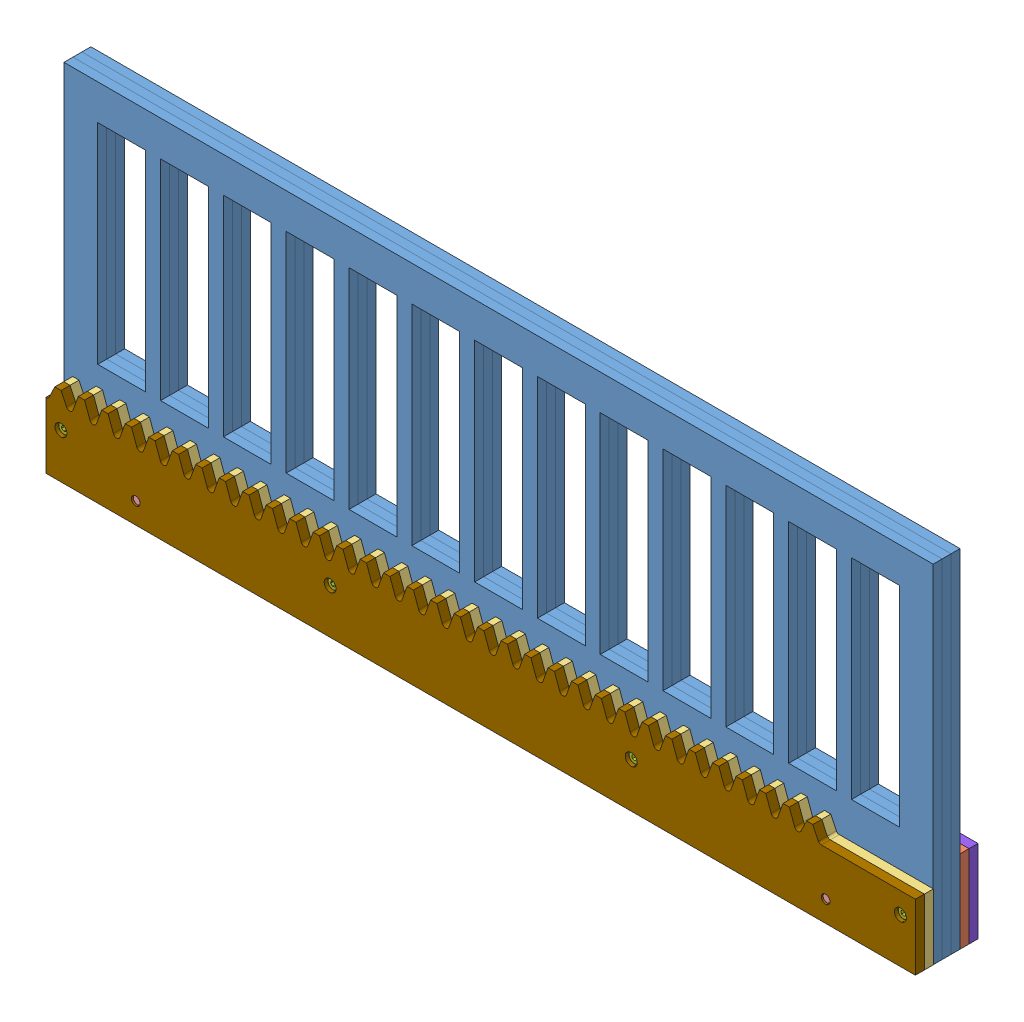
SolidWorks assembly grille-complet, configuration Défaut. Lengths in mm.
Overall size (290.66 121.96 23).
19 component instances, 9 part files, 44 mates.
Components (placement in the parent):
- grille-1: grille [Défaut] at (-123.12 -59.7841 0) size (290.6 116 3)
- grille-bas-1-1: grille-bas-1 [Défaut] at (-123.1215 -59.7841 -3) size (290.6 27.62 3)
- grille-cremaillere-1-1: grille-cremaillere-1 [Défaut] at (151.8274 -59.7841 12) x (-1 0 0) z (0 0 -1) size (290.66 27.62 3)
- grille-axe-d3x20-1: grille-axe-d3x20 [Défaut] at (-97.0485 -52.7841 -5.5) x (0.990021 0.140917 0) z (0.140917 -0.990021 0) size (3 20 3)
- grille-poulie-d20-1: grille-poulie-d20 [Défaut] at (-97.0485 -52.7841 3.2376) x (0.249924 -0.968265 0) z (-0.968265 -0.249924 0) size (20.21 12 20.21)
- grille-poulie-d20-2: grille-poulie-d20 [Défaut] at (133.5488 -52.7841 3.6069) x (0.939295 0.34311 0) z (0.34311 -0.939295 0) size (20.21 12 20.21)
- grille-axe-d3x20-2: grille-axe-d3x20 [Défaut] at (133.5488 -52.7841 -5.5) x (0.725366 0.688363 0) z (0.688363 -0.725366 0) size (3 20 3)
- ecrou-h-1: ecrou-h [6007 HU M2] at (-122.0485 -44.7841 -3) x (1 0 0) z (0 -1 0) size (4 1.6 4.62)
- vis-chc-1: vis-chc [Vis CHC M2x20] at (-122.0485 -44.7841 12) x (-0.903483 -0.428623 0) z (-0.428623 0.903483 0) size (3.8 22 3.8)
- vis-chc-2: vis-chc [Vis CHC M2x20] at (-32.0485 -44.7841 12) x (0.724363 -0.689419 0) z (-0.689419 -0.724363 0) size (3.8 22 3.8)
- vis-chc-3: vis-chc [Vis CHC M2x20] at (68.6083 -44.7841 12) x (0.282213 -0.959352 0) z (-0.959352 -0.282213 0) size (3.8 22 3.8)
- vis-chc-4: vis-chc [Vis CHC M2x20] at (158.6083 -44.7841 12) x (-0.282213 0.959352 0) z (0.959352 0.282213 0) size (3.8 22 3.8)
- grille-2: grille [Défaut] at (-123.12 -59.7841 3) size (290.6 116 3)
- grille-3: grille [Défaut] at (-123.12 -59.7841 6) size (290.6 116 3)
- grille-bas-2-1: grille-bas-2 [Défaut] at (-123.1215 -59.7841 -6) size (290.6 27.62 3)
- grille-cremaillere-2-1: grille-cremaillere-2 [Défaut] at (151.8274 -59.7841 15) x (-1 0 0) z (0 0 -1) size (290.66 27.62 3)
- ecrou-h-2: ecrou-h [6007 HU M2] at (-32.0485 -44.7841 -3) x (1 0 0) z (0 -1 0) size (4 1.6 4.62)
- ecrou-h-3: ecrou-h [6007 HU M2] at (68.6083 -44.7841 -3) x (1 0 0) z (0 -1 0) size (4 1.6 4.62)
- ecrou-h-4: ecrou-h [6007 HU M2] at (158.6083 -44.7841 -3) x (1 0 0) z (0 -1 0) size (4 1.6 4.62)
Mates (geometry in assembly coordinates):
- Coïncidente7: coincident anti-aligned: line of grille-axe-d3x20-1 through (-97.0485 -52.7841 14.3) axis (0 0 -1); line of grille-poulie-d20-1 through (-97.0485 -52.7841 3.2376) axis (0 0 1)
- Coïncidente12: coincident anti-aligned: line of Poulie D20-2 through (133.5488 -52.7841 3.6069) axis (0 0 1); line of grille-axe-d3x20-2 through (133.5488 -52.7841 14.3) axis (0 0 -1)
- Coïncidente22: coincident anti-aligned: plane of grille-1 through (-107.05 -50.784 3) normal (0 0 1); plane of grille-2 through (-107.05 -50.784 3) normal (0 0 -1)
- Coïncidente23: coincident aligned: plane of grille-1 through (-127.0485 56.2159 3) normal (0 1 0); plane of grille-2 through (-127.0485 56.2159 6) normal (0 1 0)
- Coïncidente24: coincident: line of grille-1 through (116 163.5503 -59.7841) axis (0 0 1); plane of grille-2 through (163.5503 56.2159 6) normal (1 0 0)
- Coïncidente26: coincident anti-aligned: plane of grille-2 through (-107.05 -50.784 6) normal (0 0 1); plane of grille-3 through (-107.05 -50.784 6) normal (0 0 -1)
- Coïncidente27: coincident aligned: plane of grille-2 through (-127.0485 56.2159 6) normal (0 1 0); plane of grille-3 through (-127.0485 56.2159 9) normal (0 1 0)
- Coïncidente28: coincident aligned: plane of grille-2 through (163.5503 56.2159 6) normal (1 0 0); plane of grille-3 through (163.5503 56.2159 9) normal (1 0 0)
- Coïncidente29: coincident aligned: plane of grille-1 through (-127.0485 56.2159 3) normal (-1 0 0); plane of grille-bas-1-1 through (-127.0485 -32.1591 0) normal (-1 0 0)
- Coïncidente30: coincident anti-aligned: plane of grille-1 through (-107.05 -50.784 0) normal (0 0 -1); plane of grille-bas-1-1 through (-127.0485 -59.7841 0) normal (0 0 1)
- Coïncidente32: coincident anti-aligned: plane of grille-cremaillere-1-1 through (124.3384 -36.6044 9) normal (0 0 -1); plane of grille-3 through (-107.05 -50.784 9) normal (0 0 1)
- Coïncidente33: coincident aligned: plane of grille-cremaillere-1-1 through (-127.0485 -37.7826 9) normal (-1 0 0); plane of grille-3 through (-127.0485 56.2159 9) normal (-1 0 0)
- Coïncidente35: coincident aligned: plane of grille-cremaillere-1-1 through (-127.0485 -59.7841 9) normal (0 -1 0); plane of grille-3 through (163.5503 -59.7841 9) normal (0 -1 0)
- Coïncidente36: coincident aligned: plane of grille-bas-1-1 through (-127.0485 -59.7841 0) normal (0 -1 0); plane of grille-cremaillere-1-1 through (-127.0485 -59.7841 9) normal (0 -1 0)
- Coïncidente37: coincident aligned: plane of grille-bas-1-1 through (-127.0485 -32.1591 0) normal (-1 0 0); plane of grille-bas-2-1 through (-127.0485 -32.1591 -3) normal (-1 0 0)
- Coïncidente38: coincident anti-aligned: plane of grille-bas-1-1 through (-127.0485 -59.7841 -3) normal (0 0 -1); plane of grille-bas-2-1 through (-127.0485 -59.7841 -3) normal (0 0 1)
- Coïncidente39: coincident aligned: plane of grille-bas-1-1 through (-127.0485 -32.1591 0) normal (0 1 0); plane of grille-bas-2-1 through (-127.0485 -32.1591 -3) normal (0 1 0)
- Coïncidente40: coincident aligned: plane of grille-cremaillere-1-1 through (163.6083 -37.7841 9) normal (1 0 0); plane of grille-cremaillere-2-1 through (163.6083 -37.7841 12) normal (1 0 0)
- Coïncidente41: coincident aligned: plane of grille-cremaillere-1-1 through (-127.0485 -59.7841 9) normal (0 -1 0); plane of grille-cremaillere-2-1 through (-127.0485 -59.7841 12) normal (0 -1 0)
- Coïncidente42: coincident anti-aligned: plane of grille-cremaillere-1-1 through (124.3384 -36.6044 12) normal (0 0 1); plane of grille-cremaillere-2-1 through (124.3384 -36.6044 12) normal (0 0 -1)
- Coaxiale2: concentric anti-aligned: cylinder of grille-axe-d3x20-2 through (133.5488 -52.7841 14.5) axis (0 0 -1) radius 1.5; cylinder of grille-bas-2-1 through (133.5488 -52.7841 -6) axis (0 0 1) radius 1.45
- Distance1: distance = 0.5 mm aligned: plane of grille-axe-d3x20-2 through (133.5488 -52.7841 -5.5) normal (0 0 -1); plane of grille-bas-2-1 through (-127.0485 -59.7841 -6) normal (0 0 -1)
- Coaxiale3: concentric aligned: cylinder of grille-axe-d3x20-1 through (-97.0485 -52.7841 14.5) axis (0 0 -1) radius 1.5; cylinder of grille-cremaillere-2-1 through (-97.0485 -52.7841 15) axis (0 0 -1) radius 1.45
- Distance2: distance = 0.5 mm aligned: plane of grille-axe-d3x20-1 through (-97.0485 -52.7841 -5.5) normal (0 0 -1); plane of grille-bas-2-1 through (-127.0485 -59.7841 -6) normal (0 0 -1)
- Coaxiale4: concentric aligned: cylinder of grille-cremaillere-2-1 through (-122.0485 -44.7841 12) axis (0 0 1) radius 2; cylinder of vis-chc-1 through (-122.0485 -44.7841 -8) axis (0 0 1) radius 1
- Coïncidente45: coincident anti-aligned: plane of grille-cremaillere-1-1 through (124.3384 -36.6044 12) normal (0 0 1); plane of vis-chc-1 through (-122.0485 -44.7841 12) normal (0 0 -1)
- Coaxiale7: concentric aligned: cylinder of grille-cremaillere-1-1 through (-32.0485 -44.7841 9) axis (0 0 1) radius 1; cylinder of vis-chc-2 through (-32.0485 -44.7841 -8) axis (0 0 1) radius 1
- Coaxiale8: concentric aligned: cylinder of grille-cremaillere-1-1 through (68.6083 -44.7841 9) axis (0 0 1) radius 1; cylinder of vis-chc-3 through (68.6083 -44.7841 -8) axis (0 0 1) radius 1
- Coaxiale9: concentric aligned: cylinder of grille-cremaillere-1-1 through (158.6083 -44.7841 9) axis (0 0 1) radius 1; cylinder of vis-chc-4 through (158.6083 -44.7841 -8) axis (0 0 1) radius 1
- Coïncidente46: coincident anti-aligned: plane of grille-cremaillere-1-1 through (124.3384 -36.6044 12) normal (0 0 1); plane of vis-chc-2 through (-32.0485 -44.7841 12) normal (0 0 -1)
- Coïncidente47: coincident aligned: circle of grille-cremaillere-2-1; plane of vis-chc-3 through (68.6083 -44.7841 12) normal (0 0 -1)
- Coïncidente48: coincident anti-aligned: plane of grille-cremaillere-1-1 through (124.3384 -36.6044 12) normal (0 0 1); plane of vis-chc-4 through (158.6083 -44.7841 12) normal (0 0 -1)
- Coaxiale10: concentric aligned: cylinder of ecrou-h-1 through (-122.0485 -44.7841 -4.6) axis (0 0 1) radius 0.7835; cylinder of vis-chc-1 through (-122.0485 -44.7841 -8) axis (0 0 1) radius 1
- Parallèle1: parallel anti-aligned: plane of grille-bas-2-1 through (-124.0663 -45.9491 -3) normal (1 0 0); plane of ecrou-h-1 through (-124.0485 -43.6294 -4.6) normal (-1 0 0)
- Coïncidente50: coincident anti-aligned: plane of grille-bas-1-1 through (-127.0485 -59.7841 -3) normal (0 0 -1); plane of ecrou-h-1 through (-120.0485 -43.6294 -3) normal (0 0 1)
- Coaxiale11: concentric aligned: cylinder of vis-chc-2 through (-32.0485 -44.7841 -8) axis (0 0 1) radius 1; cylinder of ecrou-h-2 through (-32.0485 -44.7841 -4.6) axis (0 0 1) radius 0.7835
- Coaxiale12: concentric aligned: cylinder of vis-chc-3 through (68.6083 -44.7841 -8) axis (0 0 1) radius 1; cylinder of ecrou-h-3 through (68.6083 -44.7841 -4.6) axis (0 0 1) radius 0.7835
- Coaxiale13: concentric aligned: cylinder of vis-chc-4 through (158.6083 -44.7841 -8) axis (0 0 1) radius 1; cylinder of ecrou-h-4 through (158.6083 -44.7841 -27.5671) axis (0 0 1) radius 0.7835
- Parallèle2: parallel anti-aligned: plane of grille-bas-2-1 through (-34.0663 -43.6191 -3) normal (0.5 -0.866025 0); plane of ecrou-h-2 through (-32.0485 -42.4747 -4.6) normal (-0.5 0.866025 0)
- Parallèle3: parallel anti-aligned: plane of grille-bas-2-1 through (66.531 -43.6191 -3) normal (0.5 -0.866025 0); plane of ecrou-h-3 through (68.6083 -42.4747 -4.6) normal (-0.5 0.866025 0)
- Parallèle4: parallel anti-aligned: plane of grille-bas-2-1 through (156.531 -43.6191 -3) normal (0.5 -0.866025 0); plane of ecrou-h-4 through (158.6083 -42.4747 -27.5671) normal (-0.5 0.866025 0)
- Coïncidente55: coincident anti-aligned: plane of grille-bas-1-1 through (-127.0485 -59.7841 -3) normal (0 0 -1); plane of ecrou-h-2 through (-30.0485 -43.6294 -3) normal (0 0 1)
- Coïncidente56: coincident anti-aligned: plane of grille-bas-1-1 through (-127.0485 -59.7841 -3) normal (0 0 -1); plane of ecrou-h-3 through (70.6083 -43.6294 -3) normal (0 0 1)
- Coïncidente57: coincident anti-aligned: plane of grille-bas-1-1 through (-127.0485 -59.7841 -3) normal (0 0 -1); plane of ecrou-h-4 through (160.6083 -43.6294 -3) normal (0 0 1)
